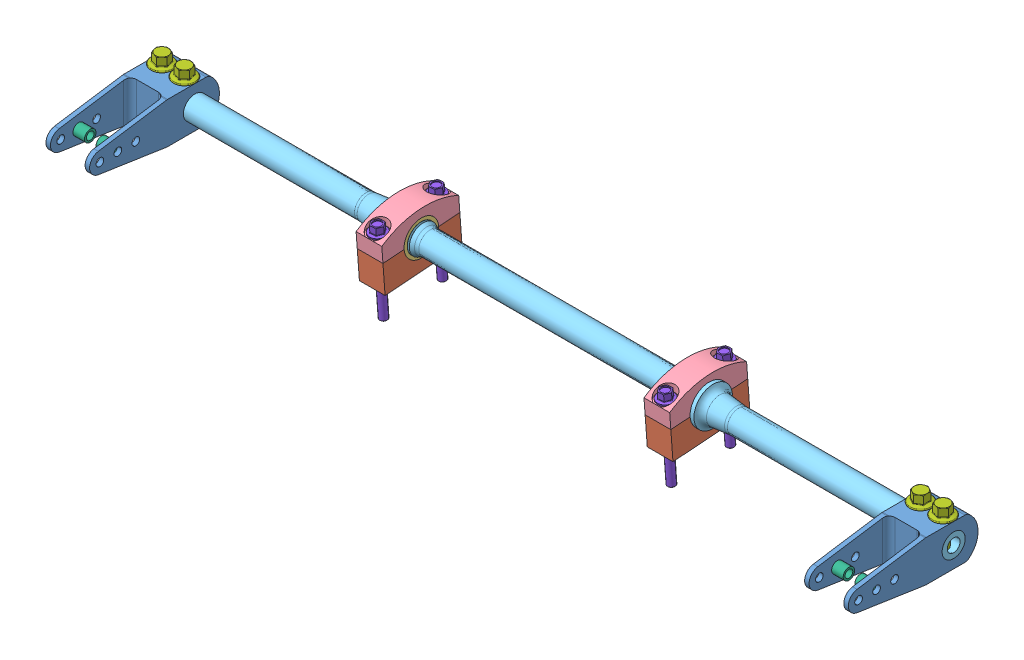
SolidWorks assembly A7310_Rear_Anti_Roll_Bar, configuration 預設. Lengths in mm.
Overall size (628.56 113.03 120.16).
23 component instances, 8 part files, 86 mates.
Components (placement in the parent):
- A7320_Rear_Clamp-3: A7320_Rear_Clamp [預設] at (278.1623 130.0897 -1492.88) x (0 0 -1) z (1 0 0) size (101 50.64 34)
- A7320_Rear_Clamp-4: A7320_Rear_Clamp [預設] at (-278.1623 130.0897 -1492.88) x (0 0 -1) z (-1 0 0) size (101 50.64 34)
- rearsupportassem-2: rearsupportassem [預設] at (114.8358 13.4181 2555.1276) x (1 0 0) z (0 0.02255 -0.999746) size (20 44.09 62.27)
  - A7320_Rear_Lower_Mount-1: A7320_Rear_Lower_Mount [預設] at (-12.8358 -204.6747 61.0563) size (20 25.59 61.08)
  - A7320_Rear_ARB_Bar_Spacer-1: A7320_Rear_ARB_Bar_Spacer [預設] at (-12.8358 -25.36 4049.6092) x (0 -0.924225 -0.381849) z (1 0 0) size (27 27 20)
  - A7320_Rear_Upper_Mount-1: A7320_Rear_Upper_Mount [預設] at (-12.8358 -204.6747 61.0563) size (20 21.6 61.11)
- rearsupportassem-3: rearsupportassem [預設] at (-114.8358 613.4623 -5513.6174) x (-1 0 0) z (0 -0.125576 0.992084) size (20 44.09 62.27) (flexible)
  - A7320_Rear_Lower_Mount-1: A7320_Rear_Lower_Mount [預設] at (-12.8358 -204.6747 61.0563) size (20 25.59 61.08)
  - A7320_Rear_ARB_Bar_Spacer-1: A7320_Rear_ARB_Bar_Spacer [預設] at (-12.8358 -25.36 4049.6092) x (0 0.912628 0.40879) z (1 0 0) size (27 27 20)
  - A7320_Rear_Upper_Mount-1: A7320_Rear_Upper_Mount [預設] at (-12.8358 -204.6747 61.0563) size (20 21.6 61.11)
- A7320_Rear_Bar-2: A7320_Rear_Bar [預設] at (-15.1727 130.0897 -1492.88) x (1 0 0) z (0 0.573483 -0.819217) size (624.32 66.54 51.08)
- A7310_ARB_Clamp_Spacer-1: A7310_ARB_Clamp_Spacer [預設] at (299.6623 130.0897 -1432.88) x (0 0 -1) z (1 0 0) size (8.9 8.9 9)
- A7310_ARB_Clamp_Spacer-6: A7310_ARB_Clamp_Spacer [預設] at (281.6623 130.0897 -1432.88) x (0 0 -1) z (1 0 0) size (8.9 8.9 9)
- A7310_ARB_Clamp_Spacer-5: A7310_ARB_Clamp_Spacer [預設] at (-290.6623 130.0897 -1432.88) x (0 0.036978 -0.999316) z (1 0 0) size (8.9 8.9 9)
- A7310_ARB_Clamp_Spacer-4: A7310_ARB_Clamp_Spacer [預設] at (-299.6623 130.0897 -1432.88) x (0 0.924225 0.381849) z (-1 0 0) size (8.9 8.9 9)
- hex flange screw_am-1: hex flange screw_am [B18.2.3.4M - Hex flange screw, M8 x 1.25 x 35 --22N] at (286.4123 154.544 -1492.88) x (0 -1 0) z (0.999683 0 -0.025171) size (43.5 17 17)
- hex flange screw_am-2: hex flange screw_am [B18.2.3.4M - Hex flange screw, M8 x 1.25 x 35 --22N] at (303.9123 154.544 -1492.88) x (0 -1 0) z (-0.231398 0 0.972859) size (43.5 17 17)
- indented hex flange head machine screw_am-2: indented hex flange head machine screw_am [AM B18.6.7M 6x60-38-N] at (112 143.724 -1514.9296) x (0 -0.997246 -0.074162) z (0.074162 -0.073957 0.9945) size (66.7 12.8 12.8)
- indented hex flange head machine screw_am-3: indented hex flange head machine screw_am [AM B18.6.7M 6x60-38-N] at (-112 140.3126 -1469.0563) x (0 -0.997246 -0.074162) z (0.074162 -0.073957 0.9945) size (66.7 12.8 12.8)
- indented hex flange head machine screw_am-4: indented hex flange head machine screw_am [AM B18.6.7M 6x60-38-N] at (-112 143.724 -1514.9296) x (0 -0.997246 -0.074162) z (0.074162 -0.073957 0.9945) size (66.7 12.8 12.8)
- indented hex flange head machine screw_am-5: indented hex flange head machine screw_am [AM B18.6.7M 6x60-38-N] at (112 140.3126 -1469.0563) x (0 -0.997246 -0.074162) z (0.074162 -0.073957 0.9945) size (66.7 12.8 12.8)
- hex flange screw_am-4: hex flange screw_am [B18.2.3.4M - Hex flange screw, M8 x 1.25 x 35 --22N] at (-303.9123 154.544 -1492.88) x (0 -1 0) z (-0.273336 0 0.961919) size (43.5 17 17)
- hex flange screw_am-5: hex flange screw_am [B18.2.3.4M - Hex flange screw, M8 x 1.25 x 35 --22N] at (-286.4123 154.544 -1492.88) x (0 -1 0) z (-0.273336 0 0.961919) size (43.5 17 17)
Mates (geometry in assembly coordinates):
- 同軸心2: concentric aligned: cylinder of bar-1 through (-316.6918 50.4656 977.3175) axis (-1 0 0) radius 12.5; cylinder of lower support base ver4-1 through (-308.4188 48.5244 978.2417) axis (-1 0 0) radius 14
- 同軸心4: concentric anti-aligned: cylinder of bar-1 through (-316.6918 50.4656 977.3175) axis (-1 0 0) radius 12.5; cylinder of spacer-1 through (-328.4188 48.5244 978.2417) axis (1 0 0) radius 12.5
- 同軸心7: concentric aligned: cylinder of lower support base ver4-2 through (25.5405 41.2385 954.8341) axis (0 0.998665 0.051655) radius 3; cylinder of upper support base ver4-2 through (25.5405 29.7391 954.2393) axis (0 0.998665 0.051655) radius 3
- 同軸心8: concentric aligned: cylinder of bar-1 through (-316.6918 50.4656 977.3175) axis (-1 0 0) radius 12.5; cylinder of lower support base ver4-2 through (35.5405 48.5244 978.2417) axis (-1 0 0) radius 14
- 重合/共線/共點8: coincident anti-aligned: plane of lower support base ver4-2 through (35.5405 46.9747 1008.2016) normal (0 -0.998665 -0.051655); plane of upper support base ver4-2 through (35.5405 46.9747 1008.2016) normal (0 0.998665 0.051655)
- 同軸心9: concentric aligned: cylinder of bar-1 through (-316.6918 50.4656 977.3175) axis (-1 0 0) radius 12.5; cylinder of upper support base ver4-2 through (35.5405 48.5244 978.2417) axis (-1 0 0) radius 14
- 同軸心10: concentric aligned: cylinder of bar-1 through (-316.6918 50.4656 977.3175) axis (-1 0 0) radius 12.5; cylinder of spacer-2 through (35.5405 48.5244 978.2417) axis (-1 0 0) radius 13
- 同軸心15: concentric anti-aligned: cylinder of bar-1 through (-316.6918 50.4656 977.3175) axis (-1 0 0) radius 12.5; cylinder of 定位片-2 through (-308.4188 48.5244 978.2417) axis (1 0 0) radius 12.5
- 重合/共線/共點38: coincident anti-aligned: plane of upper support base ver4-1 through (-308.4188 88.471 980.3079) normal (1 0 0); plane of 定位片-2 through (-308.4188 48.5244 978.2417) normal (-1 0 0)
- 同軸心16: concentric anti-aligned: cylinder of bar-1 through (-316.6918 50.4656 977.3175) axis (-1 0 0) radius 12.5; cylinder of 定位片-1 through (11.5405 48.5244 978.2417) axis (1 0 0) radius 12.5
- 重合/共線/共點39: coincident anti-aligned: plane of upper support base ver4-2 through (15.5405 88.471 980.3079) normal (-1 0 0); plane of 定位片-1 through (15.5405 48.5244 978.2417) normal (1 0 0)
- 重合/共線/共點40: coincident anti-aligned: plane of bar-1 through (-276.3365 50.4656 977.3175) normal (-1 0 0); plane of clamp tube ver2-1 through (-265.1623 133 -1492.88) normal (1 0 0)
- 同軸心17: concentric anti-aligned: cylinder of bar-1 through (-316.6918 50.4656 977.3175) axis (-1 0 0) radius 12.5; cylinder of clamp tube ver2-1 through (-285.1623 133 -1492.88) axis (1 0 0) radius 10
- 重合/共線/共點41: coincident anti-aligned: plane of bar-1 through (276.3365 50.4656 977.3175) normal (1 0 0); plane of clamp tube ver2-2 through (265.1623 133 -1492.88) normal (-1 0 0)
- 同軸心18: concentric aligned: cylinder of bar-1 through (-316.6918 50.4656 977.3175) axis (-1 0 0) radius 12.5; cylinder of clamp tube ver2-2 through (285.1623 133 -1492.88) axis (-1 0 0) radius 10
- 同軸心19: concentric aligned: cylinder of clamp tube ver2-2 through (285.1623 133 -1492.88) axis (-1 0 0) radius 10; cylinder of A7320_Rear_Clamp-3 through (312.1623 130.0897 -1492.88) axis (-1 0 0) radius 19
- 重合/共線/共點42: coincident anti-aligned: plane of clamp tube ver2-2 through (295.1623 133 -1492.88) normal (1 0 0); plane of clamp-1 through (295.1623 133 -1492.88) normal (-1 0 0)
- 重合/共線/共點43: coincident anti-aligned: plane of clamp tube ver2-1 through (-295.1623 133 -1492.88) normal (-1 0 0); plane of clamp-2 through (-295.1623 133 -1492.88) normal (1 0 0)
- 同軸心20: concentric aligned: cylinder of clamp tube ver2-1 through (-285.1623 133 -1492.88) axis (1 0 0) radius 10; cylinder of A7320_Rear_Clamp-4 through (-312.1623 130.0897 -1492.88) axis (1 0 0) radius 19
- 同軸心21: concentric anti-aligned: cylinder of lower support base ver4-1 through (-336.4188 60.3706 1000.8838) axis (0 0.998665 0.051655) radius 2.5; cylinder of heavy hex flange screw_am-1 through (-336.4188 59.5717 1000.8425) axis (0 -0.998665 -0.051655) radius 2.5
- 重合/共線/共點44: coincident anti-aligned: plane of lower support base ver4-1 through (-344.4188 65.7772 993.1528) normal (0 -0.998665 -0.051655); plane of heavy hex flange screw_am-1 through (-341.0314 65.3763 1000.9038) normal (0 0.998665 0.051655)
- 同軸心22: concentric anti-aligned: cylinder of lower support base ver4-1 through (-300.4188 60.3706 1000.8838) axis (0 0.998665 0.051655) radius 2.5; cylinder of heavy hex flange screw_am-2 through (-300.4188 59.5717 1000.8425) axis (0 -0.998665 -0.051655) radius 2.5
- 重合/共線/共點45: coincident anti-aligned: plane of lower support base ver4-1 through (-308.4188 65.7772 993.1528) normal (0 -0.998665 -0.051655); plane of heavy hex flange screw_am-2 through (-305.0314 65.3763 1000.9038) normal (0 0.998665 0.051655)
- 同軸心23: concentric anti-aligned: cylinder of lower support base ver4-1 through (-336.4188 62.6434 956.9426) axis (0 0.998665 0.051655) radius 2.5; cylinder of heavy hex flange screw_am-3 through (-336.4188 61.8445 956.9012) axis (0 -0.998665 -0.051655) radius 2.5
- 重合/共線/共點46: coincident anti-aligned: plane of lower support base ver4-1 through (-344.4188 67.2235 965.1902) normal (0 -0.998665 -0.051655); plane of heavy hex flange screw_am-3 through (-341.0314 67.6491 956.9626) normal (0 0.998665 0.051655)
- 同軸心24: concentric anti-aligned: cylinder of lower support base ver4-1 through (-300.4188 62.6434 956.9426) axis (0 0.998665 0.051655) radius 2.5; cylinder of heavy hex flange screw_am-4 through (-300.4188 61.8445 956.9012) axis (0 -0.998665 -0.051655) radius 2.5
- 重合/共線/共點47: coincident anti-aligned: plane of lower support base ver4-1 through (-308.4188 67.2235 965.1902) normal (0 -0.998665 -0.051655); plane of heavy hex flange screw_am-4 through (-305.0314 67.6491 956.9626) normal (0 0.998665 0.051655)
- 同軸心25: concentric anti-aligned: cylinder of lower support base ver4-2 through (7.5405 62.6434 956.9426) axis (0 0.998665 0.051655) radius 2.5; cylinder of heavy hex flange screw_am-5 through (7.5405 61.8445 956.9012) axis (0 -0.998665 -0.051655) radius 2.5
- 重合/共線/共點48: coincident anti-aligned: plane of lower support base ver4-2 through (-0.4595 67.2235 965.1902) normal (0 -0.998665 -0.051655); plane of heavy hex flange screw_am-5 through (2.9279 67.6491 956.9626) normal (0 0.998665 0.051655)
- 同軸心26: concentric anti-aligned: cylinder of lower support base ver4-2 through (43.5405 62.6434 956.9426) axis (0 0.998665 0.051655) radius 2.5; cylinder of heavy hex flange screw_am-6 through (43.5405 61.8445 956.9012) axis (0 -0.998665 -0.051655) radius 2.5
- 重合/共線/共點49: coincident anti-aligned: plane of lower support base ver4-2 through (35.5405 67.2235 965.1902) normal (0 -0.998665 -0.051655); plane of heavy hex flange screw_am-6 through (38.9279 67.6491 956.9626) normal (0 0.998665 0.051655)
- 同軸心27: concentric anti-aligned: cylinder of lower support base ver4-2 through (43.5405 60.3706 1000.8838) axis (0 0.998665 0.051655) radius 2.5; cylinder of heavy hex flange screw_am-7 through (43.5405 59.5717 1000.8425) axis (0 -0.998665 -0.051655) radius 2.5
- 重合/共線/共點50: coincident anti-aligned: plane of lower support base ver4-2 through (35.5405 65.7772 993.1528) normal (0 -0.998665 -0.051655); plane of heavy hex flange screw_am-7 through (38.9279 65.3763 1000.9038) normal (0 0.998665 0.051655)
- 同軸心28: concentric anti-aligned: cylinder of lower support base ver4-2 through (7.5405 60.3706 1000.8838) axis (0 0.998665 0.051655) radius 2.5; cylinder of heavy hex flange screw_am-8 through (7.5405 59.5717 1000.8425) axis (0 -0.998665 -0.051655) radius 2.5
- 重合/共線/共點51: coincident anti-aligned: plane of lower support base ver4-2 through (-0.4595 65.7772 993.1528) normal (0 -0.998665 -0.051655); plane of heavy hex flange screw_am-8 through (2.9279 65.3763 1000.9038) normal (0 0.998665 0.051655)
- 重合/共線/共點52: coincident aligned: plane of bar-1 through (0 50.4656 977.3175) normal (1 0 0)
- 重合/共線/共點53: coincident anti-aligned: plane of upper support base ver4-1 through (-308.4188 46.9747 1008.2016) normal (0 0.998665 0.051655); plane of lower support base ver4-1 through (-308.4188 46.9747 1008.2016) normal (0 -0.998665 -0.051655)
- 同軸心29: concentric aligned: cylinder of upper support base ver4-1 through (-318.4188 27.363 1000.1779) axis (0 0.998665 0.051655) radius 3; cylinder of lower support base ver4-1 through (-318.4188 38.8624 1000.7727) axis (0 0.998665 0.051655) radius 3
- 平行相距1: distance = 188 mm anti-aligned: plane of lower support base ver4-2 through (15.5405 -130.7904 -3010.3112) normal (-1 0 0); plane of lower support base ver4-1 through (-308.4188 -130.7904 -3010.3112) normal (1 0 0)
- 同軸心301: concentric aligned: cylinder of bar-1 through (-316.6918 50.4656 977.3175) axis (1 0 0) radius 12.5; cylinder of supportassem-1/heavy hex flange screw_am-1 through (292.9071 50.4656 977.3175) axis (1 0 0) radius 2.5
- 重合/共線/共點541: coincident anti-aligned: plane of bar-1 through (281.3365 50.4656 977.3175) normal (1 0 0); plane of supportassem-1/heavy hex flange screw_am-1 through (287.1071 45.8714 976.841) normal (-1 0 0)
- 同軸心33: concentric aligned: cylinder of bar-1 through (-316.6918 50.4656 977.3175) axis (1 0 0) radius 12.5; cylinder of rearsupportassem-3/A7320_Rear_ARB_Bar_Spacer-1 through (-122 130.0897 -1492.88) axis (1 0 0) radius 11
- 同軸心302: concentric anti-aligned: cylinder of rearsupportassem-2/A7320_Rear_ARB_Bar_Spacer-1 through (122 130.0897 -1492.88) axis (-1 0 0) radius 11; cylinder of A7320_Rear_Bar-2 through (-337.6182 130.0897 -1492.88) axis (1 0 0) radius 9
- 重合/共線/共點543: coincident anti-aligned: plane of clamp tube ver2-2 through (270.1623 133 -1492.88) normal (-1 0 0); plane of A7320_Rear_Bar-2 through (312.1623 130.0897 -1492.88) normal (1 0 0)
- 同軸心303: concentric aligned: cylinder of rearsupportassem-3/A7320_Rear_ARB_Bar_Spacer-1 through (-122 130.0897 -1492.88) axis (1 0 0) radius 11; cylinder of A7320_Rear_Bar-2 through (-337.6182 130.0897 -1492.88) axis (1 0 0) radius 9
- 同軸心304: concentric anti-aligned: cylinder of clamp tube ver2-2 through (285.1623 133 -1492.88) axis (-1 0 0) radius 10; cylinder of A7320_Rear_Bar-2 through (-337.6182 130.0897 -1492.88) axis (1 0 0) radius 5
- 同軸心305: concentric aligned: cylinder of clamp tube ver2-1 through (-285.1623 133 -1492.88) axis (1 0 0) radius 10; cylinder of A7320_Rear_Bar-2 through (-337.6182 130.0897 -1492.88) axis (1 0 0) radius 9
- 重合/共線/共點544: coincident aligned: plane of A7320_Rear_Bar-2 through (0 130.0897 -1492.88) normal (1 0 0)
- 平行相距2: distance = 102 mm: plane of assembly through (0 0 0) normal (1 0 0); plane of assembly; plane of rearsupportassem-2/A7320_Rear_Upper_Mount-1 through (102 90.1999 -1495.8465) normal (-1 0 0)
- 平行相距3: distance = 102 mm aligned: plane of rearsupportassem-3/A7320_Rear_Upper_Mount-1 through (-102 90.1999 -1495.8465) normal (1 0 0)
- 重合/共線/共點545: coincident anti-aligned: plane of A7320_Rear_Clamp-3 through (308.6623 130.0897 -1492.88) normal (-1 0 0); plane of ARBspacer-1 through (308.6623 130.0897 -1432.88) normal (1 0 0)
- 同軸心306: concentric aligned: cylinder of A7320_Rear_Clamp-3 through (312.1623 130.0897 -1432.88) axis (-1 0 0) radius 3; cylinder of A7310_ARB_Clamp_Spacer-1 through (308.6623 130.0897 -1432.88) axis (-1 0 0) radius 3
- 重合/共線/共點546: coincident anti-aligned: plane of A7320_Rear_Clamp-3 through (281.6623 130.0897 -1492.88) normal (1 0 0); plane of ARBspacer-2 through (281.6623 130.0897 -1432.88) normal (-1 0 0)
- 同軸心307: concentric aligned: cylinder of A7320_Rear_Clamp-3 through (312.1623 130.0897 -1432.88) axis (-1 0 0) radius 3; cylinder of A7310_ARB_Clamp_Spacer-6 through (290.6623 130.0897 -1432.88) axis (-1 0 0) radius 3
- 重合/共線/共點547: coincident anti-aligned: plane of A7320_Rear_Clamp-4 through (-308.6623 130.0897 -1492.88) normal (1 0 0); plane of ARBspacer-4 through (-308.6623 130.0897 -1432.88) normal (-1 0 0)
- 同軸心308: concentric aligned: cylinder of A7320_Rear_Clamp-4 through (-312.1623 130.0897 -1432.88) axis (1 0 0) radius 3; cylinder of A7310_ARB_Clamp_Spacer-4 through (-308.6623 130.0897 -1432.88) axis (1 0 0) radius 3
- 同軸心309: concentric anti-aligned: cylinder of A7320_Rear_Clamp-4 through (-312.1623 130.0897 -1432.88) axis (1 0 0) radius 3; cylinder of A7310_ARB_Clamp_Spacer-5 through (-281.6623 130.0897 -1432.88) axis (-1 0 0) radius 3
- 重合/共線/共點548: coincident anti-aligned: plane of A7320_Rear_Clamp-4 through (-281.6623 130.0897 -1492.88) normal (-1 0 0); plane of ARBspacer-3 through (-281.6623 130.0897 -1432.88) normal (1 0 0)
- 平行3: parallel aligned: plane of rearsupportassem-3/A7320_Rear_Lower_Mount-1 through (-122 105.4103 -1464.6325) normal (0 -0.997246 -0.074162); plane of A7320_Rear_Bar-2 through (-15.1727 89.9816 -1495.8627) normal (0 -0.997246 -0.074162)
- 平行4: parallel aligned: plane of rearsupportassem-2/A7320_Rear_Lower_Mount-1 through (122 109.86 -1524.4673) normal (0 -0.997246 -0.074162); plane of A7320_Rear_Bar-2 through (-15.1727 89.9816 -1495.8627) normal (0 -0.997246 -0.074162)
- 重合/共線/共點558: coincident anti-aligned: plane of clamp tube ver2-1 through (-265.1623 133 -1492.88) normal (1 0 0); plane of rearbar-1 through (-265.1623 133 -1492.88) normal (-1 0 0)
- 同軸心310: concentric aligned: cylinder of A7320_Rear_Clamp-4 through (-312.1623 130.0897 -1492.88) axis (1 0 0) radius 9; cylinder of A7320_Rear_Bar-2 through (-337.6182 130.0897 -1492.88) axis (1 0 0) radius 9
- 重合/共線/共點559: coincident aligned: plane of A7320_Rear_Clamp-4 through (-312.1623 130.0897 -1492.88) normal (-1 0 0); plane of A7320_Rear_Bar-2 through (-312.1623 130.0897 -1492.88) normal (-1 0 0)
- 同軸心311: concentric anti-aligned: cylinder of A7320_Rear_Clamp-3 through (312.1623 130.0897 -1492.88) axis (-1 0 0) radius 9; cylinder of A7320_Rear_Bar-2 through (-337.6182 130.0897 -1492.88) axis (1 0 0) radius 9
- 重合/共線/共點560: coincident aligned: plane of A7320_Rear_Clamp-3 through (312.1623 130.0897 -1492.88) normal (1 0 0); plane of A7320_Rear_Bar-2 through (312.1623 130.0897 -1492.88) normal (1 0 0)
- 平行5: parallel aligned: plane of A7320_Rear_Clamp-3 through (278.1623 130.0897 -1492.88) normal (0 1 0)
- 平行6: parallel anti-aligned: plane of A7320_Rear_Clamp-4 through (-278.1623 130.0897 -1492.88) normal (0 -1 0)
- 同軸心312: concentric aligned: cylinder of A7320_Rear_Clamp-3 through (286.4123 110.0897 -1492.88) axis (0 1 0) radius 4; cylinder of hex flange screw_am-1 through (286.4123 154.544 -1492.88) axis (0 1 0) radius 4
- 同軸心313: concentric aligned: cylinder of A7320_Rear_Clamp-3 through (303.9123 110.0897 -1492.88) axis (0 1 0) radius 4; cylinder of hex flange screw_am-2 through (303.9123 154.544 -1492.88) axis (0 1 0) radius 4
- 重合/共線/共點561: coincident anti-aligned: plane of A7320_Rear_Clamp-3 through (312.1623 146.044 -1492.88) normal (0 1 0); plane of hex flange screw_am-2 through (309.5291 146.044 -1491.5441) normal (0 -1 0)
- 重合/共線/共點562: coincident anti-aligned: plane of A7320_Rear_Clamp-3 through (312.1623 146.044 -1492.88) normal (0 1 0); plane of hex flange screw_am-1 through (286.267 146.044 -1498.6517) normal (0 -1 0)
- 同軸心314: concentric anti-aligned: cylinder of rearsupportassem-2/A7320_Rear_Upper_Mount-1 through (112 148.3289 -1468.4601) axis (0 -0.997246 -0.074162) radius 3; cylinder of indented hex flange head machine screw_am-5 through (112 146.1589 -1468.6215) axis (0 0.997246 0.074162) radius 3
- 重合/共線/共點563: coincident anti-aligned: plane of rearsupportassem-2/A7320_Rear_Upper_Mount-1 through (112 140.3126 -1469.0563) normal (0 0.997246 0.074162); plane of indented hex flange head machine screw_am-5 through (115.2909 140.3307 -1469.3004) normal (0 -0.997246 -0.074162)
- 同軸心315: concentric anti-aligned: cylinder of rearsupportassem-2/A7320_Rear_Upper_Mount-1 through (112 151.7404 -1514.3335) axis (0 -0.997246 -0.074162) radius 3; cylinder of indented hex flange head machine screw_am-2 through (112 149.5704 -1514.4948) axis (0 0.997246 0.074162) radius 3
- 重合/共線/共點564: coincident anti-aligned: plane of rearsupportassem-2/A7320_Rear_Upper_Mount-1 through (112 143.724 -1514.9296) normal (0 0.997246 0.074162); plane of indented hex flange head machine screw_am-2 through (115.2909 143.7422 -1515.1737) normal (0 -0.997246 -0.074162)
- 同軸心316: concentric anti-aligned: cylinder of rearsupportassem-3/A7320_Rear_Upper_Mount-1 through (-112 148.3289 -1468.4601) axis (0 -0.997246 -0.074162) radius 3; cylinder of indented hex flange head machine screw_am-3 through (-112 146.1589 -1468.6215) axis (0 0.997246 0.074162) radius 3
- 重合/共線/共點565: coincident anti-aligned: plane of rearsupportassem-3/A7320_Rear_Upper_Mount-1 through (-112 140.3126 -1469.0563) normal (0 0.997246 0.074162); plane of indented hex flange head machine screw_am-3 through (-108.7091 140.3307 -1469.3004) normal (0 -0.997246 -0.074162)
- 同軸心317: concentric anti-aligned: cylinder of rearsupportassem-3/A7320_Rear_Upper_Mount-1 through (-112 151.7404 -1514.3335) axis (0 -0.997246 -0.074162) radius 3; cylinder of indented hex flange head machine screw_am-4 through (-112 149.5704 -1514.4948) axis (0 0.997246 0.074162) radius 3
- 重合/共線/共點566: coincident anti-aligned: plane of rearsupportassem-3/A7320_Rear_Upper_Mount-1 through (-112 143.724 -1514.9296) normal (0 0.997246 0.074162); plane of indented hex flange head machine screw_am-4 through (-108.7091 143.7422 -1515.1737) normal (0 -0.997246 -0.074162)
- 同軸心318: concentric anti-aligned: cylinder of A7320_Rear_Clamp-4 through (-303.9123 150.0897 -1492.88) axis (0 -1 0) radius 4; cylinder of hex flange screw_am-4 through (-303.9123 154.544 -1492.88) axis (0 1 0) radius 4
- 重合/共線/共點567: coincident anti-aligned: plane of A7320_Rear_Clamp-4 through (-312.1623 146.044 -1492.88) normal (0 1 0); plane of hex flange screw_am-4 through (-298.3587 146.044 -1491.3019) normal (0 -1 0)
- 同軸心319: concentric anti-aligned: cylinder of A7320_Rear_Clamp-4 through (-286.4123 150.0897 -1492.88) axis (0 -1 0) radius 4; cylinder of hex flange screw_am-5 through (-286.4123 154.544 -1492.88) axis (0 1 0) radius 4
- 重合/共線/共點568: coincident anti-aligned: plane of A7320_Rear_Clamp-4 through (-312.1623 146.044 -1492.88) normal (0 1 0); plane of hex flange screw_am-5 through (-280.8587 146.044 -1491.3019) normal (0 -1 0)
- 重合/共線/共點571: coincident aligned: plane of A7320_Rear_Bar-2 through (0 130.0897 -1492.88) normal (1 0 0)
- 重合/共線/共點572: coincident aligned: plane of A7320_Rear_Bar-2 through (-15.1727 0 -1492.88) normal (0 1 0)
- 重合/共線/共點573: coincident aligned: plane of A7320_Rear_Bar-2 through (-15.1727 130.0897 0) normal (0 0 1)
